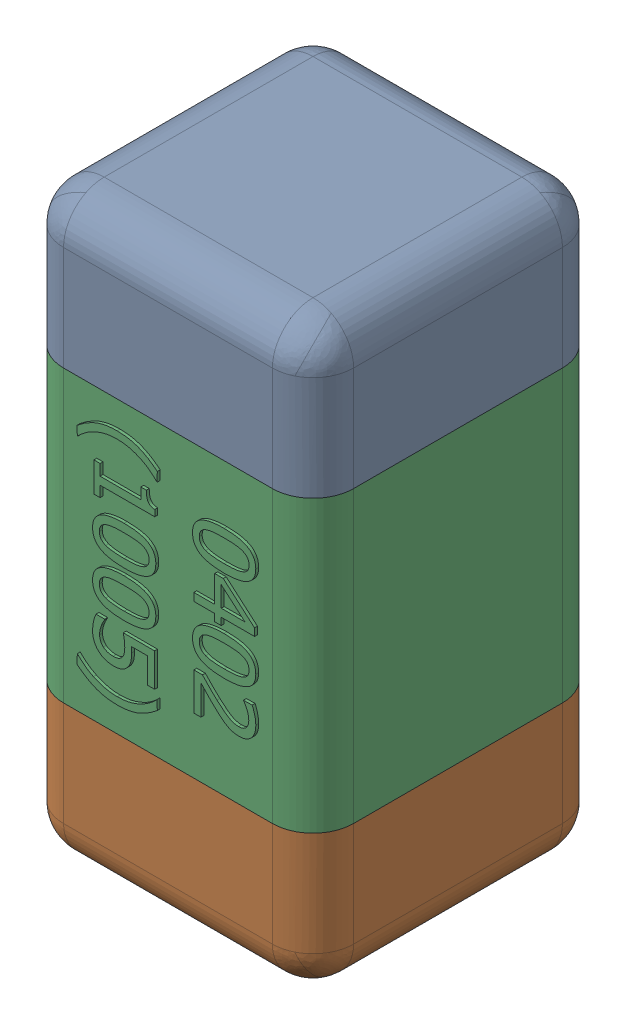
SolidWorks assembly C49, configuration Standard. Lengths in mm.
Overall size (0.51 1.01 0.51).
4 component instances, 3 part files, 0 mates.
Components (placement in the parent):
- C49-subassembly-1-1: C49-subassembly-1 [Standard] at (-9.4 -3.6001 0) x (0 -1 0) z (0 0 1) size (1.01 0.51 0.51)
  - User Library-0402_Cap-1: User Library-0402_Cap [Standard] at origin size (0.26 0.51 0.51)
  - User Library-0402_Cap-1-1: User Library-0402_Cap-1 [Standard] at origin size (0.26 0.5 0.51)
  - User Library-0402_Cap-2-1: User Library-0402_Cap-2 [Standard] at origin size (0.5 0.5 0.51)
